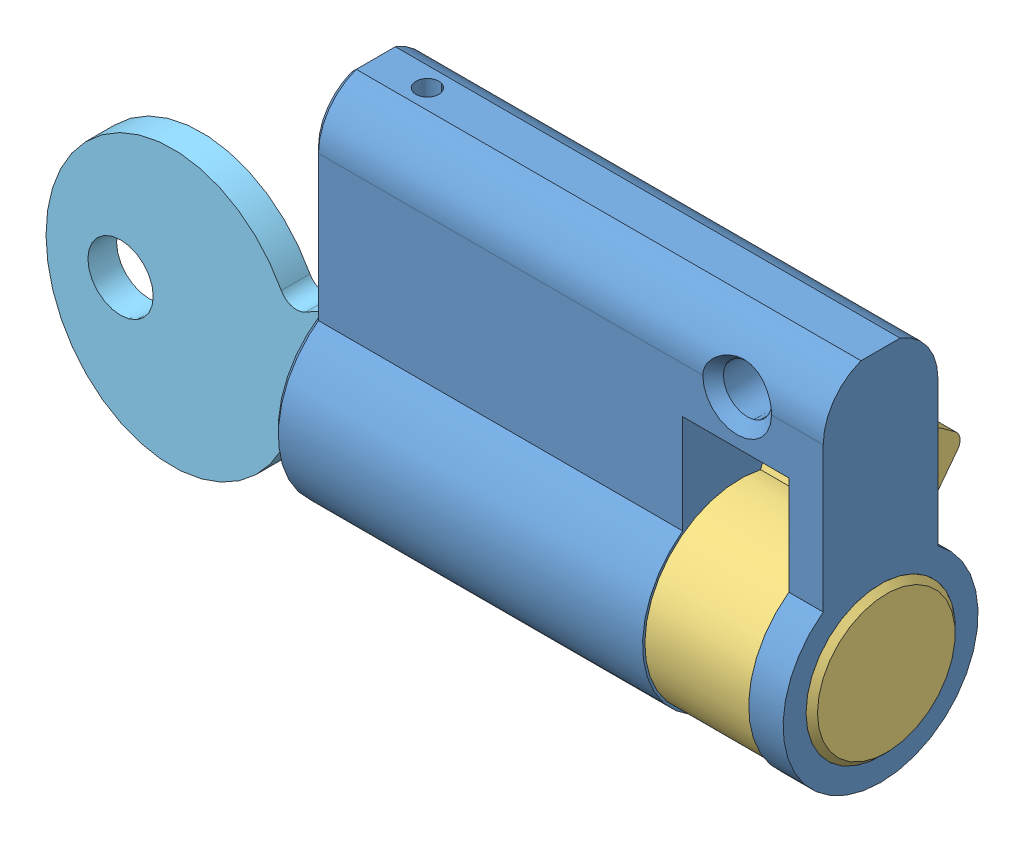
SolidWorks assembly lock_assembly_eg, configuration Default. Lengths in mm.
Overall size (72 38.45 18.44).
7 component instances, 5 part files, 4 mates.
Components (placement in the parent):
- cylinder_sub-assembly_e-1: cylinder_sub-assembly_e [Default] at origin size (44.5 32.7 17) (flexible)
  - cylinder_d-1: cylinder_d [one-pair_of_pins] at origin size (44.5 32.7 17)
  - upper_half_pin_y-1: upper_half_pin_y [cut_depth_2] at (5 15.25 0) x (0.859188 0 0.511659) z (0 -1 0) size (2 2 8)
- core_sub-assembly_g-1: core_sub-assembly_g [Default] at origin size (72 28.44 18.24)
  - core_c-1: core_c [one-pair_of_pins] at origin size (45.24 22.49 18.24)
  - lower_half_pin_x-depth_2-1: lower_half_pin_x-depth_2 [Default] at (5 7.25 0) x (0.558318 0 -0.829627) z (0.829627 0 0.558318) size (2 6.1 2)
  - key_f-1: key_f [Default] at (0 -2.25 0) x (1 0 0) z (0 -1 0) size (59.59 2.5 24)
Mates (geometry in assembly coordinates):
- front end: coincident aligned: plane of cylinder_sub-assembly_e-1/cylinder_d-1 through (0 0 0) normal (-1 0 0); plane of core_sub-assembly_g-1/core_c-1 through (0 0 0) normal (-1 0 0)
- round: concentric aligned: cylinder of cylinder_sub-assembly_e-1/cylinder_d-1 through (37 0 0) axis (-1 0 0) radius 7.25; cylinder of core_sub-assembly_g-1/core_c-1 through (32.25 0 0) axis (-1 0 0) radius 7.25
- pins alignment: concentric aligned: cylinder of cylinder_sub-assembly_e-1/upper_half_pin_y-1 through (5 7.25 0) axis (0 1 0) radius 1; cylinder of core_sub-assembly_g-1/lower_half_pin_x-depth_2-1 through (5 1.15 0) axis (0 1 0) radius 1
- pins end to end: tangent anti-aligned: plane of cylinder_sub-assembly_e-1/upper_half_pin_y-1 through (5 7.25 0) normal (0 -1 0); sphere of core_sub-assembly_g-1/lower_half_pin_x-depth_2-1
